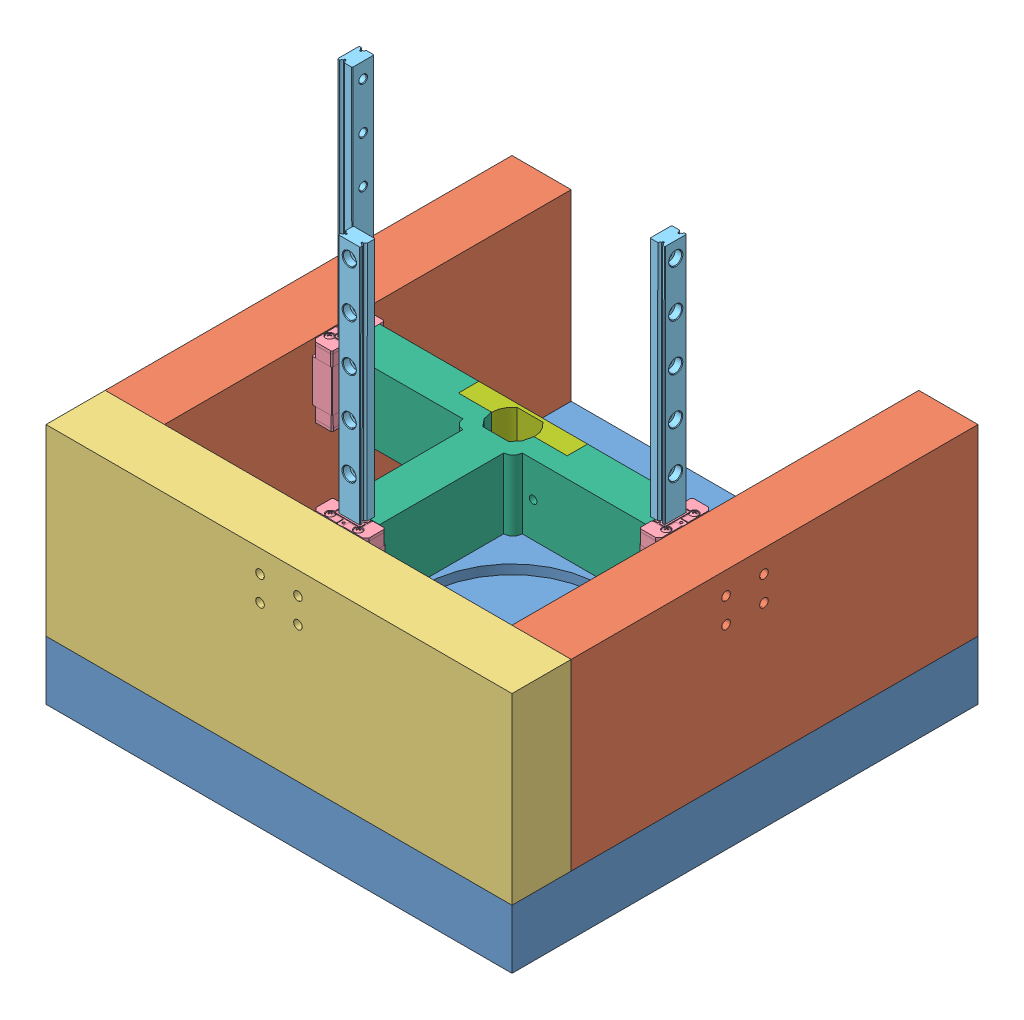
SolidWorks assembly modded test motor assembly, configuration Default. Lengths in mm.
Overall size (150 155.51 150).
12 component instances, 7 part files, 35 mates.
Components (placement in the parent):
- base_m-1: base_m [Default] at (-34.4118 60.5931 174.8572) size (150 19 150)
- railssides-1: railssides [Default] at (171.5382 138.5931 99.8572) size (19.05 59 130.95)
- rails_m-1: rails_m [Default] at (40.5882 138.5931 99.8572) size (150 59 19.05)
- railssides-2: railssides [Default] at (40.5882 138.5931 99.8572) size (19.05 59 130.95)
- MGN7C-1: MGN7C [MGN7C] at (93.1806 127.3484 99.7536) x (0 -0.000883 -1) z (0 -1 0.000883) size (17 6.5 23.31)
- MGN7C-2: MGN7C [MGN7C] at (40.6917 127.3484 152.4496) x (1 -0.000883 0) z (-0.000883 -1 0) size (17 6.5 23.31)
- MGN7C-3: MGN7C [MGN7C] at (-12.0043 127.3484 99.9607) x (0 -0.000883 1) z (0 -1 -0.000883) size (17 6.5 23.31)
- MGN7 rail-2: MGN7 rail [150 mm] at (40.7663 216.0984 149.9996) x (1 -0.000883 0) z (-0.000883 -1 0) size (7 4.8 100)
- MGN7 rail-3: MGN7 rail [150 mm] at (90.7306 216.0984 99.679) x (0 -0.000883 -1) z (0 -1 0.000883) size (7 4.8 100)
- MGN7 rail-4: MGN7 rail [150 mm] at (-9.5543 216.0984 100.0353) x (0 -0.000883 1) z (0 -1 -0.000883) size (7 4.8 100)
- topmount-4: topmount [Default] at (40.6957 116.0484 86.8746) x (-1 0 0) z (0 1 0) size (98.9 55.95 22.55)
- topmountcover-2: topmountcover [Default] at (40.6957 138.5984 86.8746) x (1 0 0) z (0 -1 0) size (35 6.55 22.55)
Mates (geometry in assembly coordinates):
- Coincident1: coincident anti-aligned: plane of base_m-1 through (-34.4118 79.5931 174.8572) normal (0 1 0); plane of rails-1 through (40.5882 79.5931 99.8572) normal (0 -1 0)
- Coincident2: coincident aligned: plane of base_m-1 through (-34.4118 79.5931 174.8572) normal (-1 0 0); plane of rails-1 through (-34.4118 79.5931 174.8572) normal (-1 0 0)
- Coincident3: coincident aligned: plane of base_m-1 through (-34.4118 79.5931 24.8572) normal (0 0 -1); plane of rails-1 through (-34.4118 79.5931 24.8572) normal (0 0 -1)
- Coincident4: coincident anti-aligned: plane of base_m-1 through (-34.4118 79.5931 174.8572) normal (0 1 0); plane of rails_m-1 through (40.5882 79.5931 99.8572) normal (0 -1 0)
- Coincident5: coincident aligned: plane of base_m-1 through (-34.4118 79.5931 174.8572) normal (0 0 1); plane of rails_m-1 through (-34.4118 79.5931 174.8572) normal (0 0 1)
- Coincident6: coincident aligned: plane of base_m-1 through (-34.4118 79.5931 174.8572) normal (-1 0 0); plane of rails_m-1 through (-34.4118 79.5931 174.8572) normal (-1 0 0)
- Coincident7: coincident anti-aligned: plane of base_m-1 through (-34.4118 79.5931 174.8572) normal (0 1 0); plane of railssides-1 through (171.5382 79.5931 99.8572) normal (0 -1 0)
- Coincident8: coincident aligned: plane of base_m-1 through (-34.4118 79.5931 24.8572) normal (0 0 -1); plane of railssides-1 through (96.5382 79.5931 24.8572) normal (0 0 -1)
- Coincident9: coincident aligned: plane of base_m-1 through (115.5882 79.5931 174.8572) normal (1 0 0); plane of railssides-1 through (115.5882 79.5931 155.8072) normal (1 0 0)
- Coincident10: coincident aligned: plane of base_m-1 through (-34.4118 79.5931 174.8572) normal (-1 0 0); plane of railssides-2 through (-34.4118 79.5931 174.8572) normal (-1 0 0)
- Coincident11: coincident aligned: plane of base_m-1 through (-34.4118 79.5931 24.8572) normal (0 0 -1); plane of railssides-2 through (-34.4118 79.5931 24.8572) normal (0 0 -1)
- Coincident13: coincident: plane of base_m-1 through (-34.4118 79.5931 174.8572) normal (0 1 0); line of railssides-2 through (-34.4118 79.5931 24.8572) axis (0 0 1)
- Coincident17: coincident anti-aligned: plane of base_m-1 through (-34.4118 79.5931 174.8572) normal (0 1 0); plane of topmount-1 through (-29.9591 79.5931 87.8126) normal (0 -1 0)
- Parallel2: parallel aligned: plane of base_m-1 through (-34.4118 79.5931 174.8572) normal (-1 0 0); plane of topmount-1 through (-88.4591 79.5931 146.3126) normal (-1 0 0)
- Parallel3: parallel aligned: plane of base_m-1 through (115.5882 79.5931 174.8572) normal (1 0 0); plane of topmount-1 through (28.5409 79.5931 146.3126) normal (1 0 0)
- Coincident20: coincident anti-aligned: plane of MGN7C-2 through (40.6857 120.5984 152.3996) normal (0 0 -1); plane of MGN7 rail-1 through (-806.5496 23890.7641 152.5072) normal (0 0 1)
- Parallel4: parallel aligned: plane of MGN7C-2 through (49.1857 120.5909 152.4496) normal (1 -0.000883 0); plane of MGN7 rail-1 through (-799.7496 23890.7641 147.9072) normal (1 0 0)
- Parallel5: parallel aligned: plane of MGN7C-2 through (32.1857 120.6059 152.4496) normal (-1 0.000883 0); plane of MGN7 rail-1 through (-806.7496 23890.7641 147.9072) normal (-1 0 0)
- Coincident23: coincident anti-aligned: plane of MGN7C-2; plane of MGN7 rail-2
- Coincident24: coincident anti-aligned: plane of MGN7C-2 through (40.6857 120.5984 152.3996) normal (0 0 -1); plane of MGN7 rail-2
- Coincident27: coincident anti-aligned: plane of MGN7 rail-2 through (37.3781 116.1013 147.5996) normal (0 0 -1); plane of topmount-2 through (36.9844 138.5931 147.7072) normal (0 0 1)
- Coincident29: coincident anti-aligned: plane of MGN7 rail-2 through (37.1781 116.1015 147.7996) normal (-1 0.000883 0); plane of topmount-2 through (36.9844 138.5931 147.7072) normal (1 0 0)
- Coincident30: coincident anti-aligned: plane of railssides-1 through (171.5382 138.5931 99.8572) normal (0 1 0); plane of topmount-2 through (40.4844 138.5931 90.7072) normal (0 -1 0)
- Coincident31: coincident anti-aligned: plane of MGN7 rail-2 through (37.3781 116.1013 147.5996) normal (0 0 -1); plane of topmount-3 through (36.9796 78.1564 147.647) normal (0 -0.001224 0.999999)
- Concentric3: concentric aligned: cylinder of MGN7 rail-2 through (40.6825 121.0984 147.5986) axis (0 0 1) radius 1.2; cylinder of topmount-3 through (40.4796 121.1125 142.6995) axis (0 -0.001224 0.999999) radius 1.25
- Coincident38: coincident anti-aligned: plane of topmount-3 through (22.9796 141.215 99.8241) normal (0 0.001224 -0.999999); plane of topmountcover-1 through (40.4796 121.215 99.7996) normal (0 -0.001224 0.999999)
- Coincident40: coincident anti-aligned: plane of topmount-3 through (57.9796 141.231 86.7241) normal (-1 0 0); plane of topmountcover-1 through (57.9796 121.2307 86.9746) normal (1 0 0)
- Coincident42: coincident aligned: plane of topmount-3 through (40.4796 141.2307 86.9991) normal (0 0.999999 0.001224); plane of topmountcover-1 through (40.4796 141.2307 86.9991) normal (0 0.999999 0.001224)
- Coincident43: coincident anti-aligned: plane of MGN7 rail-2; plane of topmount-4
- Concentric4: concentric aligned: cylinder of MGN7 rail-2 through (40.6957 136.0984 147.5986) axis (0 0 1) radius 1.2; cylinder of topmount-4 through (40.6957 136.0984 142.5996) axis (0 0 1) radius 1.25
- Coincident45: coincident anti-aligned: plane of MGN7C-3 through (-8.7543 120.5984 99.9547) normal (1 0 0); plane of topmount-4 through (-8.7543 138.5984 149.0996) normal (-1 0 0)
- Concentric6: concentric anti-aligned: cylinder of railssides-1 through (116.5382 123.3431 93.7572) axis (-1 0 0) radius 1.4; cylinder of MGN7C-1 through (93.9306 123.3431 93.7572) axis (1 0 0) radius 1
- Parallel12: parallel anti-aligned: plane of railssides-1 through (96.5382 79.5931 174.8572) normal (-1 0 0); plane of MGN7 rail-3 through (93.1306 116.1013 103.0673) normal (1 0 0)
- Coincident48: coincident anti-aligned: plane of topmount-4 through (58.1957 116.0484 99.6996) normal (0 0 -1); plane of topmountcover-2 through (40.6957 138.5984 99.6996) normal (0 0 1)
- Concentric7: concentric aligned: cylinder of topmount-4 through (53.6957 127.3234 109.6996) axis (0 0 -1) radius 1.25; cylinder of topmountcover-2 through (53.6957 127.3234 103.1496) axis (0 0 -1) radius 1.25
